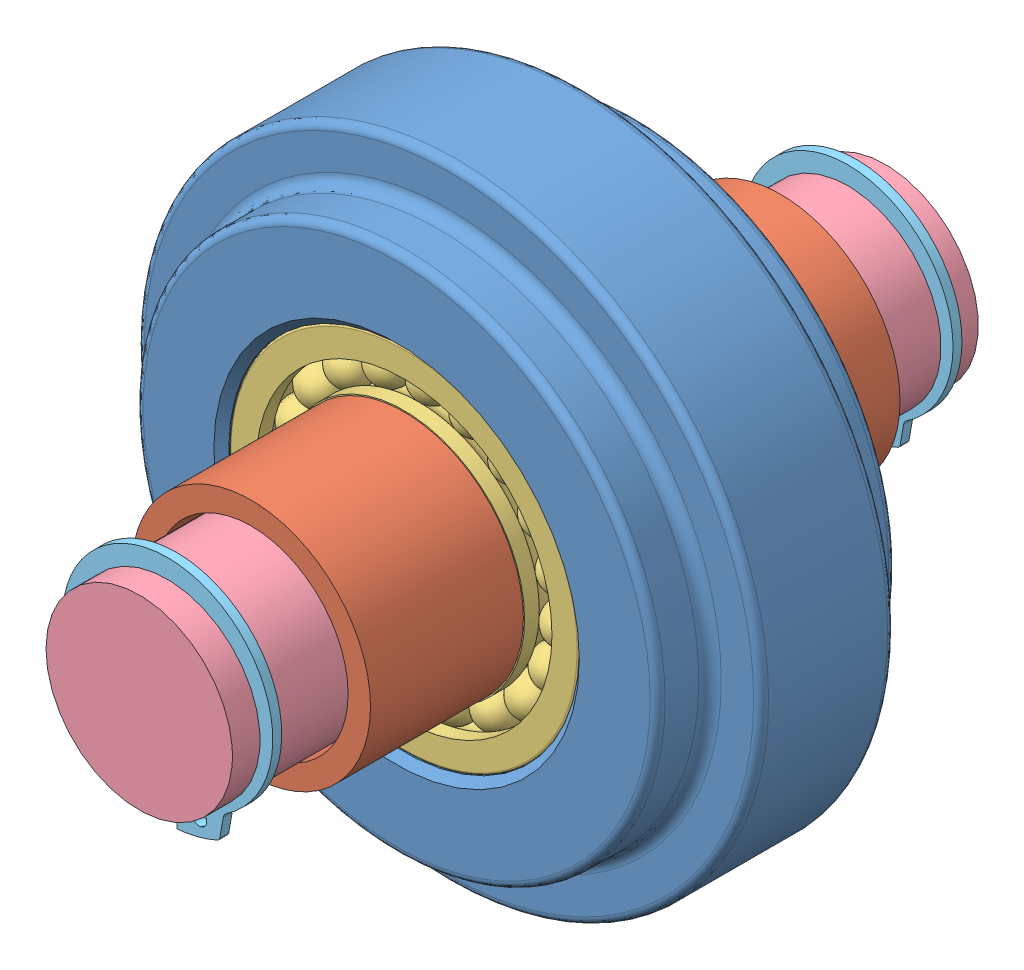
SolidWorks assembly 20A托轮装配, configuration 默认. Lengths in mm.
Overall size (83.7 83.7 100).
8 component instances, 5 part files, 14 mates.
Components (placement in the parent):
- 20A托轮-1: 20A托轮 [默认] at (1222.5689 583.4556 5353.5225) size (83.7 83.7 32)
- 转向轮轴套-1: 转向轮轴套 [默认] at (1222.5689 583.4556 5377.5) size (32 32 20.5)
- 转向轮轴套-2: 转向轮轴套 [默认] at (1222.5689 583.4556 5327) size (32 32 20.5)
- deep groove ball bearings gb-1: deep groove ball bearings gb [Rolling bearings 16005 GB 276-94] at (1222.5689 583.4556 5373.5) x (0 0 1) z (-1 0 0) size (8 47 47)
- deep groove ball bearings gb-2: deep groove ball bearings gb [Rolling bearings 16005 GB 276-94] at (1222.5689 583.4556 5351.5) x (0 0 -1) z (1 0 0) size (8 47 47)
- 转向轮轴-1: 转向轮轴 [默认] at (-86.7559 -153.1799 -95) size (25 25 100)
- circlips for shaft--type a large gb-1: circlips for shaft--type a large gb [GB_CONNECTING_PIECE_RING_RRA 25] at (1222.5689 584.2856 5318) size (28.2 30.88 1.2)
- circlips for shaft--type a large gb-2: circlips for shaft--type a large gb [GB_CONNECTING_PIECE_RING_RRA 25] at (1222.5689 584.2856 5409.2) size (28.2 30.88 1.2)
Mates (geometry in assembly coordinates):
- 同心11: concentric: cylinder of 20A托轮-1 through (1222.5689 583.4556 5369.5) axis (0 0 1) radius 23.5; cylinder of deep groove ball bearings gb-1 through (1222.5689 583.4556 5364.7893) axis (0 0 -1) radius 23.5
- 同心12: concentric: cylinder of 20A托轮-1 through (1222.5689 583.4556 5355.5) axis (0 0 -1) radius 23.5; cylinder of deep groove ball bearings gb-2 through (1222.5689 583.4556 5360.2107) axis (0 0 1) radius 23.5
- 重合11: coincident: plane of 20A托轮-1 through (1222.5689 583.4556 5369.5) normal (0 0 1); plane of deep groove ball bearings gb-1 through (1222.5689 606.9556 5369.5) normal (0 0 -1)
- 重合12: coincident: plane of 20A托轮-1 through (1222.5689 583.4556 5355.5) normal (0 0 -1); plane of deep groove ball bearings gb-2 through (1222.5689 606.9556 5355.5) normal (0 0 1)
- 同心13: concentric: cylinder of deep groove ball bearings gb-1 through (1222.5689 583.4556 5366.5286) axis (0 0 -1) radius 12.5; cylinder of 转向轮轴套-1 through (1222.5689 583.4556 5398) axis (0 0 -1) radius 13
- 重合13: coincident: plane of deep groove ball bearings gb-1 through (1222.5689 595.9556 5377.5) normal (0 0 1); plane of 转向轮轴套-1 through (1222.5689 583.4556 5377.5) normal (0 0 -1)
- 同心14: concentric: cylinder of deep groove ball bearings gb-2 through (1222.5689 583.4556 5358.4714) axis (0 0 1) radius 12.5; cylinder of 转向轮轴套-2 through (1222.5689 583.4556 5347.5) axis (0 0 -1) radius 13
- 重合14: coincident: plane of deep groove ball bearings gb-2 through (1222.5689 595.9556 5347.5) normal (0 0 -1); plane of 转向轮轴套-2 through (1222.5689 583.4556 5347.5) normal (0 0 1)
- 同心15: concentric: cylinder of 转向轮轴-1 through (1222.5689 583.4556 5413) axis (0 0 -1) radius 12.5; cylinder of deep groove ball bearings gb-1 through (1222.5689 583.4556 5366.5286) axis (0 0 -1) radius 12.5
- 距离1: distance = 15 mm: plane of 转向轮轴-1 through (1222.5689 583.4556 5413) normal (0 0 1); plane of 转向轮轴套-1 through (1222.5689 583.4556 5398) normal (0 0 1)
- 同心16: concentric: cylinder of 转向轮轴-1 through (1222.5689 583.4556 5316.7) axis (0 0 1) radius 11.45; cylinder of circlips for shaft--type a large gb-1 through (1222.5689 583.4556 5316.8) axis (0 0 1) radius 11.6
- 重合15: coincident: plane of 转向轮轴-1 through (1222.5689 583.4556 5318) normal (0 0 -1); plane of circlips for shaft--type a large gb-1 through (1222.5689 583.4556 5318) normal (0 0 1)
- 重合16: coincident: plane of 转向轮轴-1 through (1222.5689 583.4556 5408) normal (0 0 1); plane of circlips for shaft--type a large gb-2 through (1222.5689 583.4556 5408) normal (0 0 -1)
- 同心18: concentric: cylinder of 转向轮轴-1 through (1222.5689 583.4556 5409.3) axis (0 0 -1) radius 11.45; cylinder of circlips for shaft--type a large gb-2 through (1222.5689 583.4556 5408) axis (0 0 1) radius 11.6
